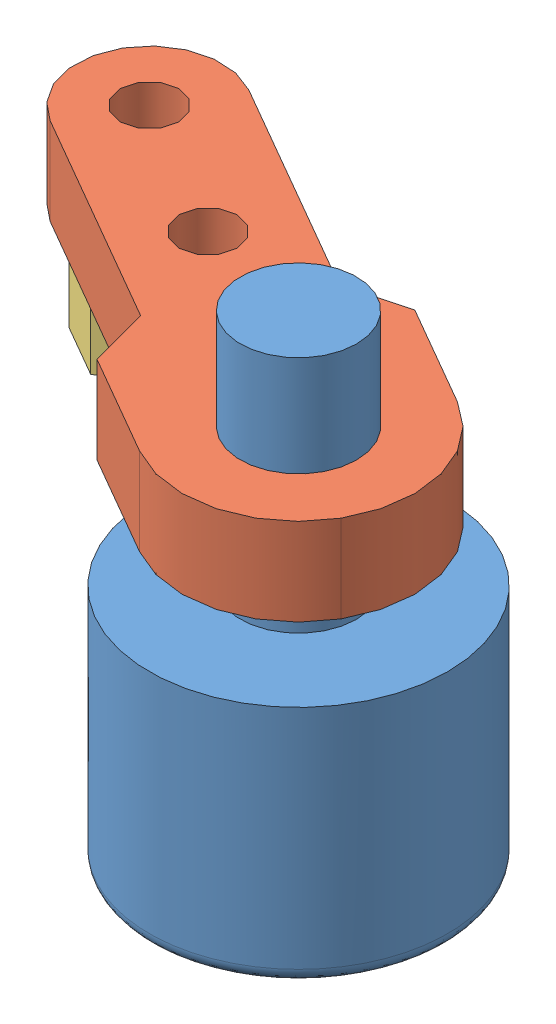
SolidWorks assembly 2018_caster_ball_assy, configuration Défaut. Lengths in mm.
Overall size (46.56 36.4 37.41).
4 component instances, 3 part files, 7 mates.
Components (placement in the parent):
- 2018_caster_ball-1: 2018_caster_ball [Défaut] at (275.7433 -3.0876 -10.4197) x (0.495869 0 0.868397) z (-0.868397 0 0.495869) size (20.5 36.4 20.5)
- 2018_frame_pt2-1: 2018_frame_pt2 [Default] at (244.6645 23 -22.5896) x (0.5 0 -0.866025) z (0 -1 0) size (16 41 6)
- 2018_Caster_ball_spacer-1: 2018_Caster_ball_spacer [Default] at (261.0209 9 -18.9197) x (0.5 0 0.866025) z (0 1 0) size (7 8.08 8)
- 2018_Caster_ball_spacer-2: 2018_Caster_ball_spacer [Default] at (251.4946 9 -24.4197) x (-0.5 0 0.866025) z (0 1 0) size (7 8.08 8)
Mates (geometry in assembly coordinates):
- Coaxiale140: concentric anti-aligned: circle of 2018_caster_ball-1; cylinder of 2018_frame_pt2-1 through (275.7433 23 -10.4197) axis (0 -1 0) radius 3.4
- Coaxiale143: concentric anti-aligned: cylinder of 2018_frame_pt2-1 through (261.0209 23 -18.9197) axis (0 -1 0) radius 2; circle of 2018_Caster_ball_spacer-1
- Coïncidente163: coincident anti-aligned: plane of 2018_frame_pt2-1 through (244.6645 17 -22.5896) normal (0 -1 0); plane of 2018_Caster_ball_spacer-1 through (261.0209 17 -18.9197) normal (0 1 0)
- Coaxiale144: concentric aligned: cylinder of 2018_frame_pt2-1 through (251.4946 23 -24.4197) axis (0 -1 0) radius 2; cylinder of 2018_Caster_ball_spacer-2 through (251.4946 17 -24.4197) axis (0 -1 0) radius 1.75
- Coïncidente165: coincident anti-aligned: plane of 2018_frame_pt2-1 through (244.6645 17 -22.5896) normal (0 -1 0); plane of 2018_Caster_ball_spacer-2 through (251.4946 17 -24.4197) normal (0 1 0)
- Parallèle9: parallel aligned: plane of 2018_frame_pt2-1 through (244.6645 17 -22.5896) normal (-0.5 0 0.866025); plane of 2018_Caster_ball_spacer-1 through (261.0209 17 -14.8783) normal (-0.5 0 0.866025)
- Parallèle10: parallel aligned: plane of 2018_frame_pt2-1 through (244.6645 17 -22.5896) normal (-0.5 0 0.866025); plane of 2018_Caster_ball_spacer-2 through (247.9946 17 -22.399) normal (-0.5 0 0.866025)
